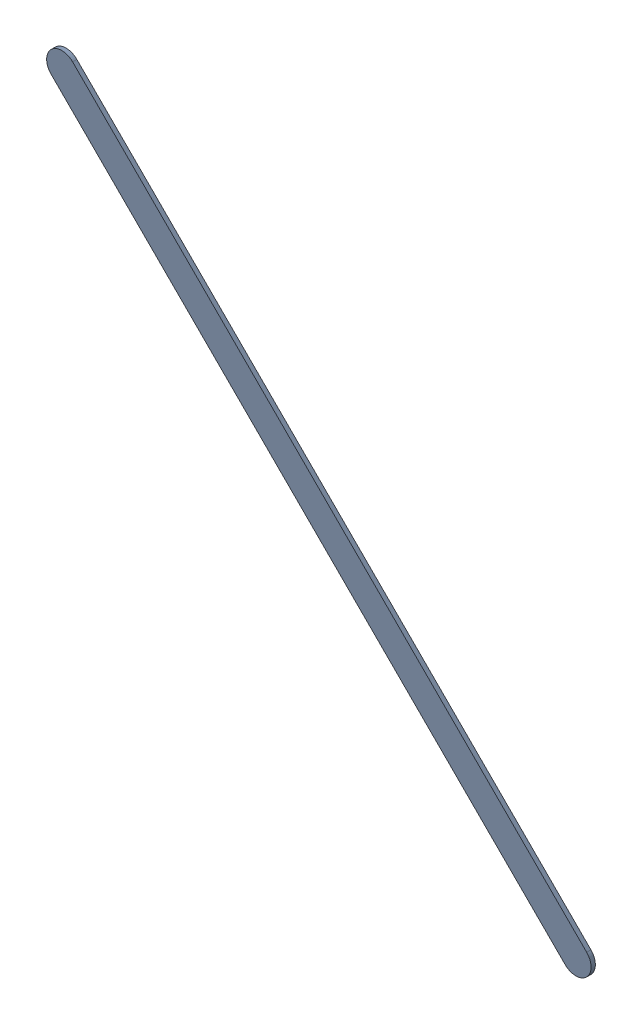
SolidWorks assembly Track (9.5mm,10.6mm)(13.8mm,6.3mm) on Top Layer, configuration Predeterminado. Lengths in mm.
Overall size (4.55 4.55 0.04).
2 component instances, 1 part files, 0 mates.
Components (placement in the parent):
- Track (9.5mm,10.6mm)(13.8mm,6.3mm) on Top Layer-1-1: Track (9.5mm,10.6mm)(13.8mm,6.3mm) on Top Layer-1 [Predeterminado] at (-68.317 -44.187 -0.0457) size (4.55 4.55 0.04)
  - Track (9.5mm,10.6mm)(13.8mm,6.3mm) on Top Layer-Part-1-1: Track (9.5mm,10.6mm)(13.8mm,6.3mm) on Top Layer-Part-1 [Predeterminado] at origin size (4.55 4.55 0.04)
